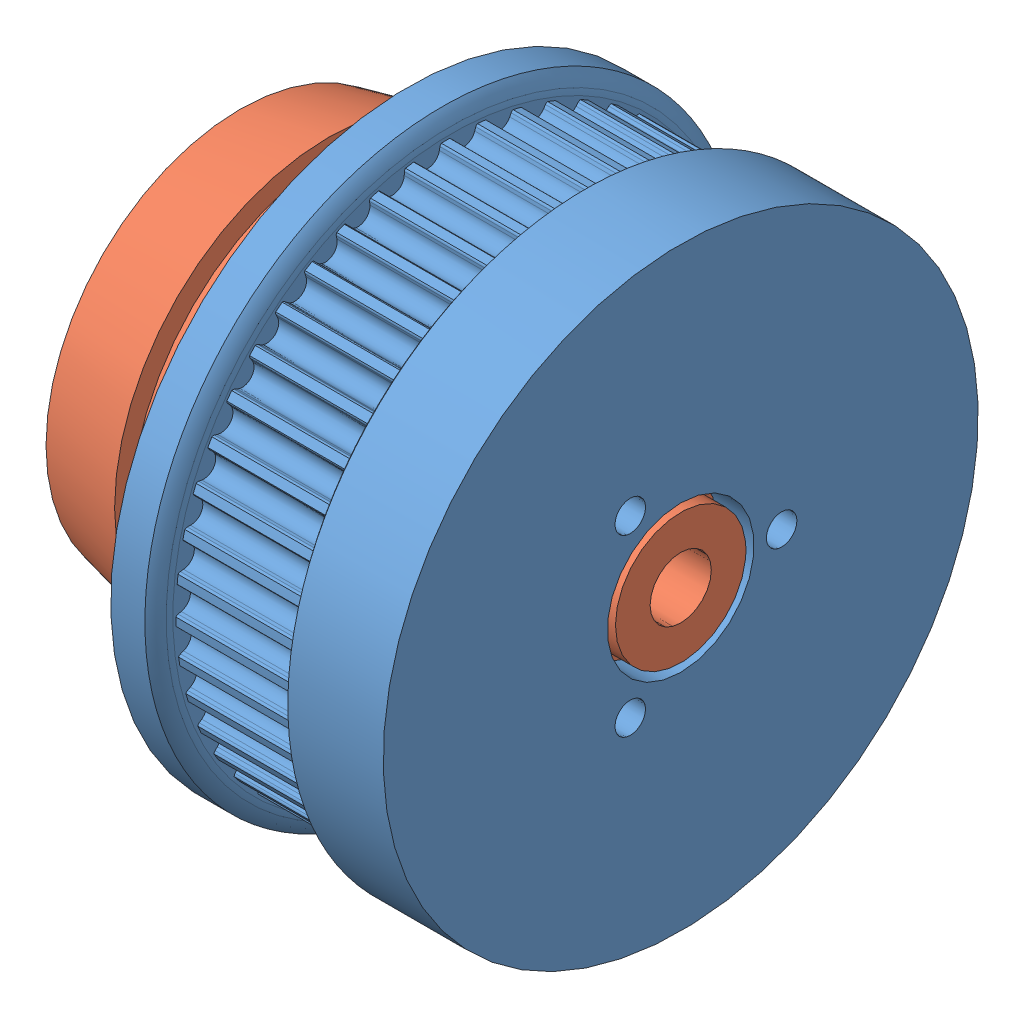
SolidWorks assembly 48tooth pully_3530 motor combo, configuration Default. Lengths in mm.
Overall size (36 48.63 48.63).
3 component instances, 2 part files, 0 mates.
Components (placement in the parent):
- 48tooth pully_3530 motor combo.step-1: 48tooth pully_3530 motor combo.step [Default] at origin size (36 48.63 48.63)
  - 3mm 48tooth GT2 Printable v2.step-1: 3mm 48tooth GT2 Printable v2.step [Default] at (23.364 0 0) x (0 1 0) z (0 0 1) size (48.63 22.27 48.63)
  - Motor_3536.step-1: Motor_3536.step [Default] at origin size (36 35 35)
